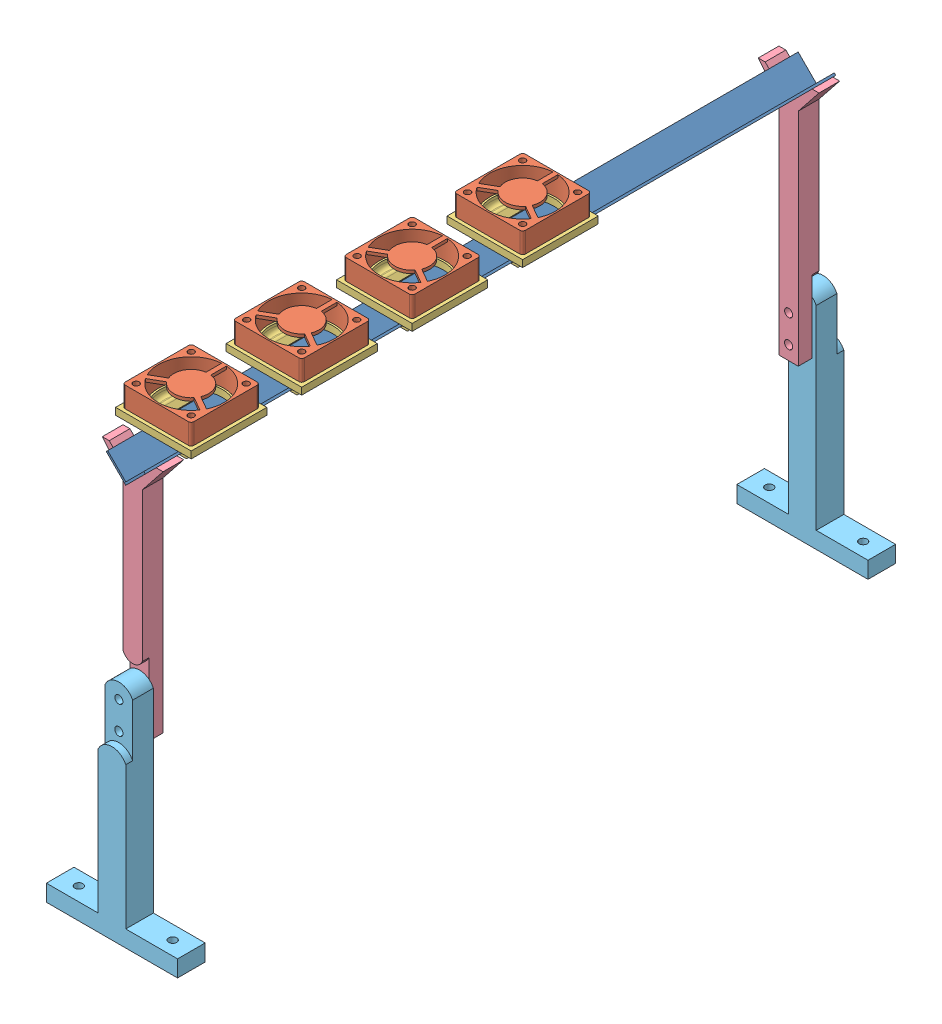
SolidWorks assembly Cooling Assembly V2, configuration Default. Lengths in mm.
Overall size (95 320.35 520).
13 component instances, 5 part files, 17 mates.
Components (placement in the parent):
- 20x20x1.5mm_Al-extrusion-1: 20x20x1.5mm_Al-extrusion [Half 0.5m] x (0.707107 0.707107 0) z (0 0 1) size (20 20 500)
- Axial-fan-1: Axial-fan [Default] at (0 25.2028 -47.375) size (74.93 14.9 57.96)
- AxialFan-Mount-1: AxialFan-Mount [Default] at (0 25.2028 -47.375) x (-1 0 0) z (0 -1 0) size (54.75 54.75 18)
- AxialFan-Mount-2: AxialFan-Mount [Default] at (0 25.2028 -127.375) x (-1 0 0) z (0 -1 0) size (54.75 54.75 18)
- AxialFan-Mount-3: AxialFan-Mount [Default] at (0 25.2028 -207.375) x (-1 0 0) z (0 -1 0) size (54.75 54.75 18)
- AxialFan-Mount-4: AxialFan-Mount [Default] at (0 25.2028 -287.375) x (-1 0 0) z (0 -1 0) size (54.75 54.75 18)
- Axial-fan-2: Axial-fan [Default] at (0 25.2028 -127.375) size (74.93 14.9 57.96)
- Axial-fan-3: Axial-fan [Default] at (0 25.2028 -207.375) size (74.93 14.9 57.96)
- Axial-fan-4: Axial-fan [Default] at (0 25.2028 -287.375) size (74.93 14.9 57.96)
- AlExtrusion_Y-Mount-1: AlExtrusion_Y-Mount [Default] at (0 1 -20) size (44 178.83 15)
- Y-Bracket_Frame-1: Y-Bracket_Frame [Default] at (0 1 -10) size (95 159.42 20)
- AlExtrusion_Y-Mount-2: AlExtrusion_Y-Mount [Default] at (0 1 -480) x (-1 0 0) z (0 0 -1) size (44 178.83 15)
- Y-Bracket_Frame-2: Y-Bracket_Frame [Default] at (0 1 -490) x (-1 0 0) z (0 0 -1) size (95 159.42 20)
Mates (geometry in assembly coordinates):
- Angle1: planar angle = 2.356194 rad: plane of assembly through (0 0 0) normal (0 1 0); plane of assembly; plane of 20x20x1.5mm_Al-extrusion-1 through (0 0 -500) normal (0.707107 -0.707107 0)
- InPlace1: in place: plane of ? through (0 18.0407 -24.875) normal (0 -1 0); plane of ? through (0 18.0407 0) normal (0 -1 0); moOrthogonalPlaneRef_w of ? through (0 18.0407 -24.875) normal (0 -1 0); plane of ? through (0 18.0407 0) normal (0 0 -1); plane of ? through (0 18.0407 -24.875) normal (0 -1 0); plane of ? through (0 18.0407 0) normal (-1 0 0); plane of Axial-fan-1 through (0 25.2028 -47.375) normal (0 -1 0); unknown of AxialFan-Mount-1
- Coincident4: coincident aligned: plane of Axial-fan-1; plane of AxialFan-Mount-1
- Coincident5: coincident aligned: moOrthogonalPlaneRef_w of Axial-fan-1 through (0 25.2028 -47.375) normal (0 0 -1); plane of AxialFan-Mount-1 through (0 25.2028 -47.375) normal (0 0 -1)
- Coincident6: coincident anti-aligned: moOrthogonalPlaneRef_w of Axial-fan-1 through (0 25.2028 -47.375) normal (1 0 0); plane of AxialFan-Mount-1 through (0 25.2028 -47.375) normal (-1 0 0)
- Coincident19: coincident: line of 20x20x1.5mm_Al-extrusion-1 through (-13.0815 15.2028 -500) axis (0 0 1); plane of AxialFan-Mount-1 through (0 15.2028 -47.375) normal (0 -1 0)
- Parallel9: parallel anti-aligned: plane of AxialFan-Mount-1 through (0 15.2028 -47.375) normal (0 -1 0)
- Coincident27: coincident: line of assembly; point of 20x20x1.5mm_Al-extrusion-1; line of AxialFan-Mount-1 through (0 15.2028 -20) axis (0 0 -1)
- Parallel12: parallel aligned: line of 20x20x1.5mm_Al-extrusion-1 through (14.1421 14.1421 -500) axis (0 0 1); line of AxialFan-Mount-1 through (27.375 20.2028 -74.75) axis (0 0 1)
- Distance5: distance = 20 mm aligned: plane of AxialFan-Mount-1 through (-27.375 20.2028 -20) normal (0 0 1); plane of 20x20x1.5mm_Al-extrusion-1 through (0 0 0) normal (0 0 1)
- InPlace3: in place: plane of assembly through (0 -3.1374 10) normal (0 0 1); plane of ? through (0 0 10) normal (0 0 1); plane of assembly through (0 -3.1374 10) normal (0 0 1); plane of ? through (0 0 10) normal (0 1 0); plane of assembly through (0 -3.1374 10) normal (0 0 1); plane of ? through (0 0 10) normal (1 0 0); plane of AlExtrusion_Y-Mount-1 through (0 -106.83 -10) normal (0 0 1); unknown of Y-Bracket_Frame-1
- Coincident33: coincident aligned: plane of AlExtrusion_Y-Mount-1; plane of Y-Bracket_Frame-1
- Coincident34: coincident aligned: moOrthogonalPlaneRef_w of AlExtrusion_Y-Mount-1 through (0 1 -10) normal (0 1 0); plane of Y-Bracket_Frame-1 through (0 1 -10) normal (0 1 0)
- Coincident35: coincident anti-aligned: moOrthogonalPlaneRef_w of AlExtrusion_Y-Mount-1 through (0 1 -10) normal (-1 0 0); plane of Y-Bracket_Frame-1 through (0 1 -10) normal (1 0 0)
- Coincident36: coincident anti-aligned: plane of 20x20x1.5mm_Al-extrusion-1 through (0 0 -500) normal (0.707107 -0.707107 0); plane of AlExtrusion_Y-Mount-1 through (17 17 -5) normal (-0.707107 0.707107 0)
- Coincident37: coincident anti-aligned: line of 20x20x1.5mm_Al-extrusion-1 through (0 0 -500) axis (0 0 1); line of AlExtrusion_Y-Mount-1 through (0 0 -5) axis (0 0 -1)
- Distance6: distance = 5 mm aligned: plane of AlExtrusion_Y-Mount-1 through (0 1 -5) normal (0 0 1); plane of 20x20x1.5mm_Al-extrusion-1 through (0 0 0) normal (0 0 1)
